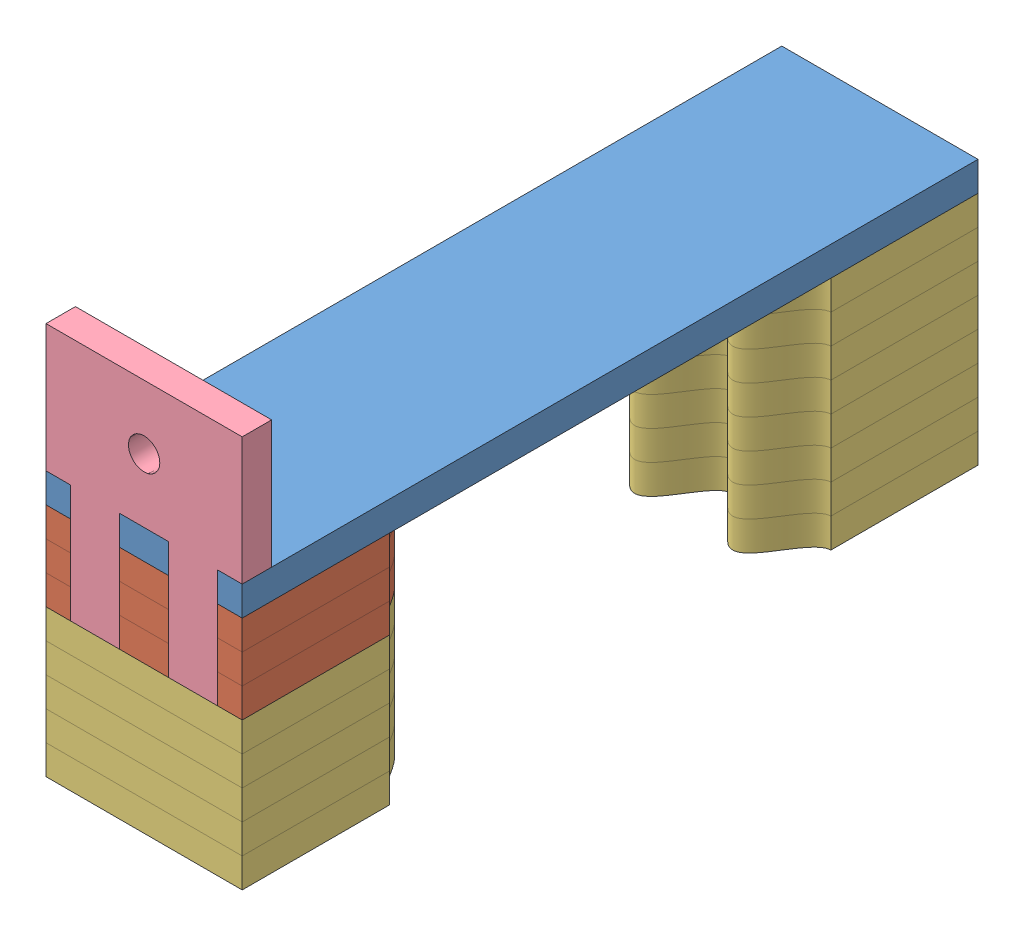
SolidWorks assembly piston, configuration Default. Lengths in mm.
Overall size (20 40 75).
18 component instances, 4 part files, 51 mates.
Components (placement in the parent):
- tooth-strip-1: tooth-strip [Default] at (26.7289 41.9083 55.3369) size (20 3 75)
- tooth-piston-1: tooth-piston [Default] at (26.7289 35.9083 82.8369) x (-1 0 0) z (0 0 -1) size (20 3 20.01)
- tooth-piston-2: tooth-piston [Default] at (26.7289 38.9083 82.8369) x (-1 0 0) z (0 0 -1) size (20 3 20.01)
- tooth-end-1: tooth-end [Default] at (26.7289 38.9083 27.8369) size (20 3 20.01)
- tooth-end-2: tooth-end [Default] at (26.7289 35.9083 27.8369) size (20 3 20.01)
- tooth-piston-3: tooth-piston [Default] at (26.7289 32.9083 82.8369) x (-1 0 0) z (0 0 -1) size (20 3 20.01)
- tooth-end-3: tooth-end [Default] at (26.7289 32.9083 27.8369) size (20 3 20.01)
- stopper-1: stopper [Default] at (16.7289 32.9083 89.8369) x (1 0 0) z (0 -1 0) size (20 3 25)
- tooth-end-4: tooth-end [Default] at (26.7289 29.9083 27.8369) size (20 3 20.01)
- tooth-end-5: tooth-end [Default] at (26.7289 29.9083 82.8369) x (-1 0 0) z (0 0 -1) size (20 3 20.01)
- tooth-end-6: tooth-end [Default] at (26.7289 26.9083 27.8369) size (20 3 20.01)
- tooth-end-7: tooth-end [Default] at (26.7289 23.9083 27.8369) size (20 3 20.01)
- tooth-end-8: tooth-end [Default] at (26.7289 26.9083 82.8369) x (-1 0 0) z (0 0 -1) size (20 3 20.01)
- tooth-end-9: tooth-end [Default] at (26.7289 23.9083 82.8369) x (-1 0 0) z (0 0 -1) size (20 3 20.01)
- tooth-end-10: tooth-end [Default] at (26.7289 20.9083 27.8369) size (20 3 20.01)
- tooth-end-11: tooth-end [Default] at (26.7289 17.9083 27.8369) size (20 3 20.01)
- tooth-end-12: tooth-end [Default] at (26.7289 20.9083 82.8369) x (-1 0 0) z (0 0 -1) size (20 3 20.01)
- tooth-end-13: tooth-end [Default] at (26.7289 17.9083 82.8369) x (-1 0 0) z (0 0 -1) size (20 3 20.01)
Mates (geometry in assembly coordinates):
- Coincident1: coincident anti-aligned: plane of tooth-strip-1 through (26.7289 41.9083 55.3369) normal (0 -1 0); plane of tooth-piston-2 through (26.7289 41.9083 82.8369) normal (0 1 0)
- Coincident2: coincident aligned: plane of tooth-strip-1 through (36.7289 44.9083 92.8369) normal (1 0 0); plane of tooth-piston-2 through (36.7289 41.9083 72.8369) normal (1 0 0)
- Coincident3: coincident aligned: plane of tooth-strip-1 through (16.7289 44.9083 92.8369) normal (0 0 1); plane of tooth-piston-2 through (36.7289 41.9083 92.8369) normal (0 0 1)
- Coincident4: coincident anti-aligned: plane of tooth-piston-1 through (26.7289 38.9083 82.8369) normal (0 1 0); plane of tooth-piston-2 through (26.7289 38.9083 82.8369) normal (0 -1 0)
- Coincident5: coincident aligned: plane of tooth-piston-1 through (36.7289 38.9083 72.8369) normal (1 0 0); plane of tooth-piston-2 through (36.7289 41.9083 72.8369) normal (1 0 0)
- Coincident6: coincident aligned: plane of tooth-piston-1 through (36.7289 38.9083 92.8369) normal (0 0 1); plane of tooth-piston-2 through (36.7289 41.9083 92.8369) normal (0 0 1)
- Coincident7: coincident anti-aligned: plane of tooth-strip-1 through (26.7289 41.9083 55.3369) normal (0 -1 0); plane of tooth-end-1 through (26.7289 41.9083 27.8369) normal (0 1 0)
- Coincident8: coincident aligned: plane of tooth-strip-1 through (16.7289 44.9083 17.8369) normal (0 0 -1); plane of tooth-end-1 through (16.7289 41.9083 17.8369) normal (0 0 -1)
- Coincident9: coincident aligned: plane of tooth-strip-1 through (36.7289 44.9083 92.8369) normal (1 0 0); plane of tooth-end-1 through (36.7289 41.9083 37.8369) normal (1 0 0)
- Coincident10: coincident anti-aligned: plane of tooth-end-1 through (26.7289 38.9083 27.8369) normal (0 -1 0); plane of tooth-end-2 through (26.7289 38.9083 27.8369) normal (0 1 0)
- Coincident11: coincident aligned: plane of tooth-end-1 through (36.7289 41.9083 37.8369) normal (1 0 0); plane of tooth-end-2 through (36.7289 38.9083 37.8369) normal (1 0 0)
- Coincident12: coincident aligned: plane of tooth-end-1 through (16.7289 41.9083 17.8369) normal (0 0 -1); plane of tooth-end-2 through (16.7289 38.9083 17.8369) normal (0 0 -1)
- Coincident17: coincident anti-aligned: plane of tooth-piston-1 through (26.7289 35.9083 82.8369) normal (0 -1 0); plane of tooth-piston-3 through (26.7289 35.9083 82.8369) normal (0 1 0)
- Coincident18: coincident aligned: plane of tooth-piston-1 through (36.7289 38.9083 72.8369) normal (1 0 0); plane of tooth-piston-3 through (36.7289 35.9083 72.8369) normal (1 0 0)
- Coincident19: coincident aligned: plane of tooth-piston-1 through (36.7289 38.9083 92.8369) normal (0 0 1); plane of tooth-piston-3 through (36.7289 35.9083 92.8369) normal (0 0 1)
- Coincident20: coincident anti-aligned: plane of tooth-end-2 through (26.7289 35.9083 27.8369) normal (0 -1 0); plane of tooth-end-3 through (26.7289 35.9083 27.8369) normal (0 1 0)
- Coincident21: coincident aligned: plane of tooth-end-2 through (36.7289 38.9083 37.8369) normal (1 0 0); plane of tooth-end-3 through (36.7289 35.9083 37.8369) normal (1 0 0)
- Coincident22: coincident aligned: plane of tooth-end-2 through (16.7289 38.9083 17.8369) normal (0 0 -1); plane of tooth-end-3 through (16.7289 35.9083 17.8369) normal (0 0 -1)
- Coincident23: coincident anti-aligned: plane of tooth-strip-1 through (29.2289 44.9083 89.8369) normal (0 0 1); plane of stopper-1 through (16.7289 32.9083 89.8369) normal (0 0 -1)
- Coincident25: coincident anti-aligned: plane of tooth-strip-1 through (26.7289 44.9083 55.3369) normal (0 1 0); plane of stopper-1 through (29.2289 44.9083 89.8369) normal (0 -1 0)
- Coincident26: coincident anti-aligned: plane of tooth-piston-1 through (34.2289 35.9083 92.8369) normal (-1 0 0); plane of stopper-1 through (34.2289 44.9083 89.8359) normal (1 0 0)
- Coincident27: coincident anti-aligned: plane of tooth-piston-3 through (26.7289 32.9083 82.8369) normal (0 -1 0); plane of tooth-end-5 through (26.7289 32.9083 82.8369) normal (0 1 0)
- Coincident28: coincident aligned: plane of tooth-piston-3 through (36.7289 35.9083 72.8369) normal (1 0 0); plane of tooth-end-5 through (36.7289 32.9083 72.8369) normal (1 0 0)
- Coincident29: coincident aligned: plane of tooth-piston-3 through (36.7289 35.9083 92.8369) normal (0 0 1); plane of tooth-end-5 through (36.7289 32.9083 92.8369) normal (0 0 1)
- Coincident30: coincident anti-aligned: plane of tooth-end-3 through (26.7289 32.9083 27.8369) normal (0 -1 0); plane of tooth-end-4 through (26.7289 32.9083 27.8369) normal (0 1 0)
- Coincident31: coincident aligned: plane of tooth-end-3 through (16.7289 35.9083 17.8369) normal (0 0 -1); plane of tooth-end-4 through (16.7289 32.9083 17.8369) normal (0 0 -1)
- Coincident33: coincident anti-aligned: plane of tooth-end-5 through (26.7289 29.9083 82.8369) normal (0 -1 0); plane of tooth-end-8 through (26.7289 29.9083 82.8369) normal (0 1 0)
- Coincident34: coincident aligned: plane of tooth-end-5 through (36.7289 32.9083 92.8369) normal (0 0 1); plane of tooth-end-8 through (36.7289 29.9083 92.8369) normal (0 0 1)
- Coincident35: coincident aligned: plane of tooth-end-5 through (36.7289 32.9083 72.8369) normal (1 0 0); plane of tooth-end-8 through (36.7289 29.9083 72.8369) normal (1 0 0)
- Coincident36: coincident anti-aligned: plane of tooth-end-8 through (26.7289 26.9083 82.8369) normal (0 -1 0); plane of tooth-end-9 through (26.7289 26.9083 82.8369) normal (0 1 0)
- Coincident37: coincident aligned: plane of tooth-end-8 through (36.7289 29.9083 92.8369) normal (0 0 1); plane of tooth-end-9 through (36.7289 26.9083 92.8369) normal (0 0 1)
- Coincident38: coincident aligned: plane of tooth-end-8 through (36.7289 29.9083 72.8369) normal (1 0 0); plane of tooth-end-9 through (36.7289 26.9083 72.8369) normal (1 0 0)
- Coincident39: coincident anti-aligned: plane of tooth-end-4 through (26.7289 29.9083 27.8369) normal (0 -1 0); plane of tooth-end-6 through (26.7289 29.9083 27.8369) normal (0 1 0)
- Coincident40: coincident aligned: plane of tooth-end-4 through (16.7289 32.9083 17.8369) normal (0 0 -1); plane of tooth-end-6 through (16.7289 29.9083 17.8369) normal (0 0 -1)
- Coincident41: coincident aligned: plane of tooth-end-4 through (36.7289 32.9083 37.8369) normal (1 0 0); plane of tooth-end-6 through (36.7289 29.9083 37.8369) normal (1 0 0)
- Coincident42: coincident anti-aligned: plane of tooth-end-6 through (26.7289 26.9083 27.8369) normal (0 -1 0); plane of tooth-end-7 through (26.7289 26.9083 27.8369) normal (0 1 0)
- Coincident43: coincident aligned: plane of tooth-end-6 through (16.7289 29.9083 17.8369) normal (0 0 -1); plane of tooth-end-7 through (16.7289 26.9083 17.8369) normal (0 0 -1)
- Coincident44: coincident aligned: plane of tooth-end-6 through (36.7289 29.9083 37.8369) normal (1 0 0); plane of tooth-end-7 through (36.7289 26.9083 37.8369) normal (1 0 0)
- Coincident45: coincident anti-aligned: plane of tooth-end-9 through (26.7289 23.9083 82.8369) normal (0 -1 0); plane of tooth-end-12 through (26.7289 23.9083 82.8369) normal (0 1 0)
- Coincident46: coincident aligned: plane of tooth-end-9 through (36.7289 26.9083 92.8369) normal (0 0 1); plane of tooth-end-12 through (36.7289 23.9083 92.8369) normal (0 0 1)
- Coincident47: coincident aligned: plane of tooth-end-9 through (36.7289 26.9083 72.8369) normal (1 0 0); plane of tooth-end-12 through (36.7289 23.9083 72.8369) normal (1 0 0)
- Coincident48: coincident anti-aligned: plane of tooth-end-12 through (26.7289 20.9083 82.8369) normal (0 -1 0); plane of tooth-end-13 through (26.7289 20.9083 82.8369) normal (0 1 0)
- Coincident49: coincident aligned: plane of tooth-end-12 through (36.7289 23.9083 92.8369) normal (0 0 1); plane of tooth-end-13 through (36.7289 20.9083 92.8369) normal (0 0 1)
- Coincident50: coincident aligned: plane of tooth-end-12 through (36.7289 23.9083 72.8369) normal (1 0 0); plane of tooth-end-13 through (36.7289 20.9083 72.8369) normal (1 0 0)
- Coincident51: coincident anti-aligned: plane of tooth-end-7 through (26.7289 23.9083 27.8369) normal (0 -1 0); plane of tooth-end-10 through (26.7289 23.9083 27.8369) normal (0 1 0)
- Coincident52: coincident aligned: plane of tooth-end-7 through (16.7289 26.9083 17.8369) normal (0 0 -1); plane of tooth-end-10 through (16.7289 23.9083 17.8369) normal (0 0 -1)
- Coincident53: coincident aligned: plane of tooth-end-7 through (36.7289 26.9083 37.8369) normal (1 0 0); plane of tooth-end-10 through (36.7289 23.9083 37.8369) normal (1 0 0)
- Coincident54: coincident anti-aligned: plane of tooth-end-10 through (26.7289 20.9083 27.8369) normal (0 -1 0); plane of tooth-end-11 through (26.7289 20.9083 27.8369) normal (0 1 0)
- Coincident55: coincident aligned: plane of tooth-end-10 through (36.7289 23.9083 37.8369) normal (1 0 0); plane of tooth-end-11 through (36.7289 20.9083 37.8369) normal (1 0 0)
- Coincident56: coincident aligned: plane of tooth-end-10 through (16.7289 23.9083 17.8369) normal (0 0 -1); plane of tooth-end-11 through (16.7289 20.9083 17.8369) normal (0 0 -1)
- Coincident57: coincident aligned: plane of tooth-end-3 through (36.7289 35.9083 37.8369) normal (1 0 0); plane of tooth-end-4 through (36.7289 32.9083 37.8369) normal (1 0 0)
